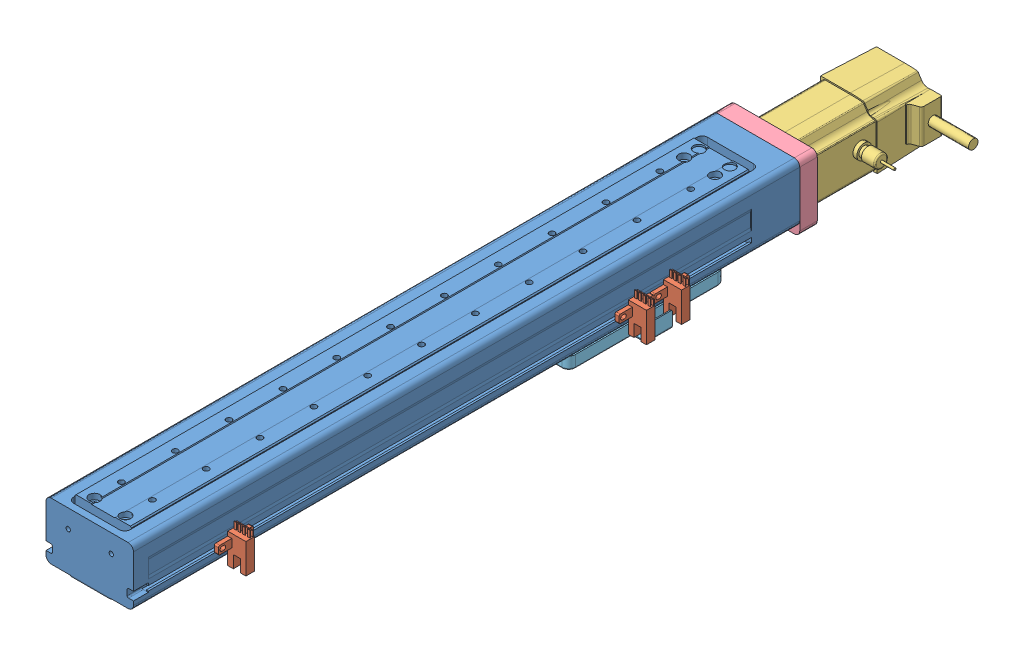
SolidWorks assembly S6M-BC-100W, configuration 默认. Lengths in mm.
Overall size (91.2 56 604.76).
7 component instances, 5 part files, 24 mates.
Components (placement in the parent):
- S6-BC滑块滑轨(CPC)^S6M-BC-100W-1: S6-BC滑块滑轨(CPC)^S6M-BC-100W [默认] x (-1 0 0) z (0 0 1) size (65 49.9 495) (virtual)
- 传感器^S6M-BC-100W-1: 传感器^S6M-BC-100W [默认] at (39.25 -38.164 392.7) size (13.5 27.2 26.1) (virtual)
- 传感器^S6M-BC-100W-2: 传感器^S6M-BC-100W [默认] at (39.25 -38.164 69) size (13.5 27.2 26.1) (virtual)
- 传感器^S6M-BC-100W-3: 传感器^S6M-BC-100W [默认] at (39.25 -38.164 95.1) size (13.5 27.2 26.1) (virtual)
- 复件 M10^S6M-BC-100W-1: 复件 M10^S6M-BC-100W [默认] at (0 -28.9 -95) x (0 -1 0) z (0 0 -1) size (42.1 79.78 121.76) (virtual)
- S6-BC-M10电机座^S6M-BC-100W-1: S6-BC-M10电机座^S6M-BC-100W [默认] at (0 -28.9 -26) x (1 0 0) z (0 0 -1) size (65 53.32 13) (virtual)
- S6-BC-ASSM滑块组件^S6M-BC-100W-1: S6-BC-ASSM滑块组件^S6M-BC-100W [Default] at (0 -1.5 167.7) x (1 0 0) z (0 1 0) size (69.5 116 25.18) (virtual)
Mates (geometry in assembly coordinates):
- 重合136: coincident: plane of 传感器^S6M-BC-100W-2 through (35.5 -30.264 85.2) normal (0 0 1); plane of 传感器^S6M-BC-100W-3 through (35.5 -30.264 85.2) normal (0 0 -1)
- 重合137: coincident: plane of 传感器^S6M-BC-100W-2 through (32.5 -49.264 75.3) normal (0 -1 0); plane of 传感器^S6M-BC-100W-3 through (32.5 -49.264 101.4) normal (0 -1 0)
- 重合141: coincident: plane of 传感器^S6M-BC-100W-1 through (32.5 -49.264 399) normal (0 -1 0); plane of 传感器^S6M-BC-100W-3 through (32.5 -49.264 101.4) normal (0 -1 0)
- 重合143: coincident: plane of 复件 M10^S6M-BC-100W-1 through (1.4978 -106.8984 -39) normal (0 0 1); plane of S6-BC-M10电机座^S6M-BC-100W-1 through (32.5 -50.4 -39) normal (0 0 -1)
- 重合147: coincident: plane of S6-BC-ASSM滑块组件^S6M-BC-100W-1; plane of assembly through (0 0 0) normal (1 0 0)
- 距离1: distance = 70 mm: plane of 传感器^S6M-BC-100W-1 through (46 -27.064 399) normal (0 0 1); plane of S6-BC滑块滑轨(CPC)^S6M-BC-100W-1 through (0 0 469) normal (0 0 1)
- 距离2: distance = 56 mm: plane of S6-BC-ASSM滑块组件^S6M-BC-100W-1 through (21 -56 105.2) normal (0 -1 0); plane of S6-BC滑块滑轨(CPC)^S6M-BC-100W-1 through (0 0 459) normal (0 1 0)
- 重合150: coincident: plane of S6-BC滑块滑轨(CPC)^S6M-BC-100W-1 through (28.5 -1.4 -67.6611) normal (0 1 0); plane of S6-BC-M10电机座^S6M-BC-100W-1 through (-32.5 -1.4 -39) normal (0 1 0)
- 重合152: coincident: plane of S6-BC滑块滑轨(CPC)^S6M-BC-100W-1 through (23 -49.9 -26) normal (0 0 -1); plane of S6-BC-M10电机座^S6M-BC-100W-1 through (32.5 -50.4 -26) normal (0 0 1)
- 重合153: coincident: plane of S6-BC滑块滑轨(CPC)^S6M-BC-100W-1 through (32.5 -39.9 -67.6611) normal (1 0 0); plane of S6-BC-M10电机座^S6M-BC-100W-1 through (32.5 -1.4 -39) normal (1 0 0)
- 重合154: coincident: plane of S6-BC滑块滑轨(CPC)^S6M-BC-100W-1 through (28.5 -1.4 -67.6611) normal (0 1 0); plane of S6-BC-M10电机座^S6M-BC-100W-1 through (-32.5 -1.4 -39) normal (0 1 0)
- 距离4: distance = 27.064 mm: plane of 传感器^S6M-BC-100W-2 through (32.5 -27.064 75.3) normal (0 1 0); plane of S6-BC滑块滑轨(CPC)^S6M-BC-100W-1 through (0 0 459) normal (0 1 0)
- 重合157: coincident: plane of S6-BC滑块滑轨(CPC)^S6M-BC-100W-1; plane of S6-BC-ASSM滑块组件^S6M-BC-100W-1
- 重合158: coincident: plane of S6-BC滑块滑轨(CPC)^S6M-BC-100W-1; plane of assembly through (0 0 0) normal (1 0 0)
- 重合159: coincident: plane of S6-BC滑块滑轨(CPC)^S6M-BC-100W-1; plane of assembly through (0 0 0) normal (0 1 0)
- 重合160: coincident: plane of S6-BC滑块滑轨(CPC)^S6M-BC-100W-1 through (0 0 0) normal (0 0 1); plane of assembly through (0 0 0) normal (0 0 1)
- 重合162: coincident: plane of 传感器^S6M-BC-100W-1 through (32.5 -27.064 399) normal (0 1 0); plane of 传感器^S6M-BC-100W-3 through (32.5 -27.064 101.4) normal (0 1 0)
- 重合163: coincident: plane of 传感器^S6M-BC-100W-1 through (32.5 -49.264 399) normal (-1 0 0); plane of 传感器^S6M-BC-100W-3 through (32.5 -49.264 101.4) normal (-1 0 0)
- 重合164: coincident: plane of 传感器^S6M-BC-100W-1 through (32.5 -49.264 399) normal (-1 0 0); plane of 传感器^S6M-BC-100W-2 through (32.5 -49.264 75.3) normal (-1 0 0)
- 重合165: coincident: plane of S6-BC滑块滑轨(CPC)^S6M-BC-100W-1 through (32.5 -39.9 -67.6611) normal (1 0 0); plane of 传感器^S6M-BC-100W-1 through (32.5 -49.264 399) normal (-1 0 0)
- 距离5: distance = 108 mm: plane of 传感器^S6M-BC-100W-2 through (46 -27.064 69) normal (0 0 -1); plane of S6-BC-M10电机座^S6M-BC-100W-1 through (32.5 -50.4 -39) normal (0 0 -1)
- 宽度1: width: plane of 传感器^S6M-BC-100W-2 through (46 -27.064 75.3) normal (0 0 1); plane of 传感器^S6M-BC-100W-3 through (46 -27.064 95.1) normal (0 0 -1); plane of S6-BC-ASSM滑块组件^S6M-BC-100W-1 through (28.75 -49.4 75.7) normal (0 0 -1); plane of S6-BC-ASSM滑块组件^S6M-BC-100W-1 through (28.75 -49.4 94.7) normal (0 0 1)
- 同心1: concentric: cylinder of 复件 M10^S6M-BC-100W-1 through (16.2635 -12.6365 -39) axis (0 0 1) radius 2.25; cylinder of S6-BC-M10电机座^S6M-BC-100W-1 through (16.2635 -12.6365 -39) axis (0 0 -1) radius 1.65
- 同心2: concentric: cylinder of 复件 M10^S6M-BC-100W-1 through (-16.2635 -45.1635 -39) axis (0 0 1) radius 2.25; cylinder of S6-BC-M10电机座^S6M-BC-100W-1 through (-16.2635 -45.1635 -39) axis (0 0 -1) radius 1.65
